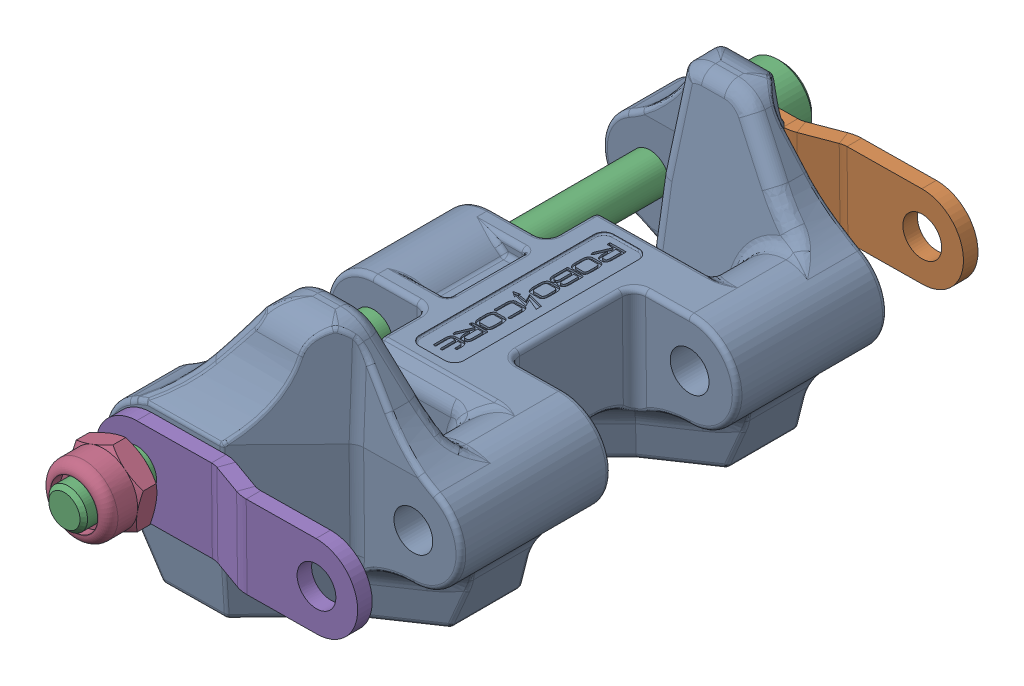
SolidWorks assembly TRAKTOR_Track_Componentes-V2, configuration Default. Lengths in mm.
Overall size (30.08 26.28 74).
5 component instances, 4 part files, 3 mates.
Components (placement in the parent):
- Esteira-Traktor-ELEMENTO-V2-25: Esteira-Traktor-ELEMENTO-V2 [Default] at (29.9982 -38.3079 0) x (-0.99994 -0.01097 0) z (0 0 -1) size (29.8 25.95 58)
- Reforco-tirante-Angulado(Valor predeterminado)-37: Reforco-tirante-Angulado(Valor predeterminado) [Default] at (29.9982 -38.3079 -29.7933) x (-0.99994 -0.01097 0) z (0 0 1) size (28.5 8.5 3)
- socket head cap screw_am(B18.3.1M - 4 x 0.7 x 70 Hex SHCS -- 20NHX)-19: socket head cap screw_am(B18.3.1M - 4 x 0.7 x 70 Hex SHCS -- 20NHX) [Default] at (19.9988 -38.4176 -35.9962) x (0 0 1) z (-0.823084 0.56792 0) size (74 7 7)
- prevailing torque nut thin insert_din(DIN EN ISO 10511 - M4 - N)-6: prevailing torque nut thin insert_din(DIN EN ISO 10511 - M4 - N) [Default] at (19.9988 -38.4176 33.9462) x (0.987369 -0.158435 0) z (0 0 1) size (7 8.08 5)
- Reforco-tirante-Angulado(Valor predeterminado)-51: Reforco-tirante-Angulado(Valor predeterminado) [Default] at (29.9982 -38.3079 31.2029) x (0.99994 0.01097 0) z (0 0 1) size (28.5 8.5 3)
Mates (geometry in assembly coordinates):
- Concentric2: concentric: cylinder of socket head cap screw_am(B18.3.1M - 4 x 0.7 x 70 Hex SHCS -- 20NHX)-19 through (19.9988 -38.4176 -67.7462) axis (0 0 -1) radius 2; cylinder of Reforco-tirante-Angulado(Valor predeterminado)-51 through (19.4276 -38.1521 -29) axis (0 0 1) radius 2
- Coincident2: coincident: plane of Esteira-Traktor-ELEMENTO-V2-25 through (39.9976 -38.1982 29) normal (0 0 1); plane of Reforco-tirante-Angulado(Valor predeterminado)-51 through (29.4276 -38.1521 -29) normal (0 0 -1)
- Concentric3: concentric aligned: cylinder of Reforco-tirante-Angulado(Valor predeterminado)-37 through (39.9976 -38.1982 -31.9962) axis (0 0 1) radius 2; cylinder of Reforco-tirante-Angulado(Valor predeterminado)-51 through (39.9976 -38.1982 29) axis (0 0 1) radius 2
